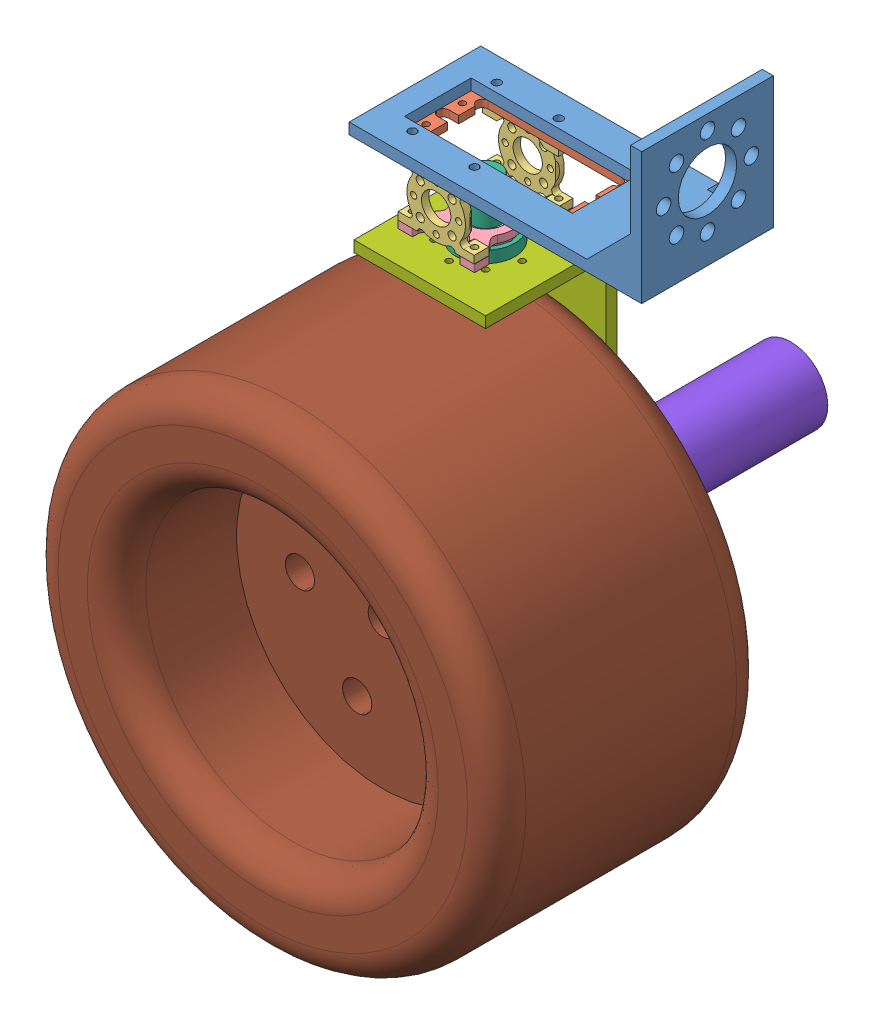
SolidWorks assembly Front_wheel_SUBASSEM, configuration Default. Lengths in mm.
Overall size (203.2 317.83 229.31).
18 component instances, 11 part files, 21 mates.
Components (placement in the parent):
- Servo_base_front-1: Servo_base_front [Default] at (66.9376 47.4067 44.7676) size (127 57.15 57.15)
- servo_mount-1: servo_mount [Default] at (63.4948 44.2317 73.3426) size (79.25 3.17 42.93)
- wheel_hold_left_right-1: wheel_hold_left_right [Default] at (47.8121 31.5317 51.8796) x (0 -1 0) z (-1 0 0) size (25.4 6.35 33.02)
- wheel_hold_left_right-2: wheel_hold_left_right [Default] at (47.8121 31.5317 94.8056) x (0 1 0) z (-1 0 0) size (25.4 6.35 33.02)
- Bearing_mount_subsubass-1: Bearing_mount_subsubass [Default] at (82.6306 37.2877 87.6325) x (0 0 -1) z (-1 0 0) size (42.93 5.08 33.27)
  - 535182-1: 535182 [Default] at (14.2899 18.456 34.8186) size (42.93 5.08 33.27)
  - .5 x .75 non flanged bearing-1: .5 x .75 non flanged bearing [Default] at (14.2899 19.5736 34.8186) x (0.770155 0 0.637857) z (-0.637857 0 0.770155) size (19.05 3.91 19.05)
- Mounting_hub_circular_servo-1: Mounting_hub_circular_servo [Default] at (47.8121 8.9765 73.3426) x (-0.707107 0 -0.707107) z (0.707107 0 -0.707107) size (25.39 25.4 25.39)
- Wheel_extension_sheet-2: Wheel_extension_sheet [Default] at (19.2371 8.9765 101.9176) size (57.15 139.7 57.15)
- Motor_and_mount_subass-1: Motor_and_mount_subass [Default] at (28.0226 -206.4882 -27.8911) x (0.696282 0.717769 0) z (0 0 1) size (46.7 46.7 115)
  - Motors-1: Motors [Default] at (81.834 51.8135 -31.3435) size (32 32 115)
  - Motor_mount-2: Motor_mount [Default] at (45.268 5.1287 35.3702) x (-0.707107 -0.707107 0) z (-0.707107 0.707107 0) size (33.02 8.74 33.02)
    - 555174-1: 555174 [Default] at (-58.8675 33.2863 7.1552) size (33.02 4.05 33.02)
    - 555174 screw_92005A116-1: 555174 screw_92005A116 [Default] at (-68.0596 28.5563 -2.0369) x (1 0 0) z (0 1 0) size (6 6 8.48)
    - 555174 screw_92005A116-2: 555174 screw_92005A116 [Default] at (-68.0596 28.5563 16.3474) x (0 0 -1) z (0 1 0) size (6 6 8.48)
    - 555174 screw_92005A116-3: 555174 screw_92005A116 [Default] at (-49.6753 28.5563 16.3474) x (-1 0 0) z (0 1 0) size (6 6 8.48)
    - 555174 screw_92005A116-4: 555174 screw_92005A116 [Default] at (-49.6753 28.5563 -2.0369) x (0 0 1) z (0 1 0) size (6 6 8.48)
- wheel_exa_1-1: wheel_exa_1 [Default] at (47.8121 -111.6735 55.7793) size (203.2 203.2 116.84)
Mates (geometry in assembly coordinates):
- Concentric1: concentric anti-aligned: cylinder of Servo_base_front-1 through (61.2824 47.4067 91.6306) axis (0 1 0) radius 1.778; cylinder of servo_mount-1 through (61.2824 47.4067 91.6306) axis (0 -1 0) radius 1.778
- Concentric2: concentric anti-aligned: cylinder of Servo_base_front-1 through (34.3417 47.4067 91.6306) axis (0 1 0) radius 1.778; cylinder of servo_mount-1 through (34.3417 47.4067 91.6306) axis (0 -1 0) radius 1.778
- Concentric3: concentric anti-aligned: cylinder of Servo_base_front-1 through (61.2824 47.4067 55.0546) axis (0 1 0) radius 1.778; cylinder of servo_mount-1 through (61.2824 47.4067 55.0546) axis (0 -1 0) radius 1.778
- Coincident1: coincident anti-aligned: plane of Servo_base_front-1 through (17.1576 47.4067 101.9176) normal (0 -1 0); plane of servo_mount-1 through (55.8849 47.4067 54.1021) normal (0 1 0)
- Concentric4: concentric aligned: cylinder of servo_mount-1 through (61.2824 47.4067 55.0546) axis (0 -1 0) radius 1.778; cylinder of wheel_hold_left_right-1 through (61.2824 40.938 55.0546) axis (0 -1 0) radius 1.3526
- Concentric5: concentric anti-aligned: cylinder of servo_mount-1 through (34.3417 47.4067 55.0546) axis (0 -1 0) radius 1.778; cylinder of wheel_hold_left_right-1 through (34.3417 44.2317 55.0546) axis (0 1 0) radius 1.3526
- Coincident2: coincident anti-aligned: plane of servo_mount-1 through (55.8849 44.2317 54.1021) normal (0 -1 0); plane of wheel_hold_left_right-1 through (47.8121 44.2317 39.7407) normal (0 1 0)
- Concentric6: concentric aligned: cylinder of servo_mount-1 through (34.3417 47.4067 91.6306) axis (0 -1 0) radius 1.778; cylinder of wheel_hold_left_right-2 through (34.3417 40.938 91.6306) axis (0 -1 0) radius 1.3526
- Concentric7: concentric anti-aligned: cylinder of servo_mount-1 through (61.2824 47.4067 91.6306) axis (0 -1 0) radius 1.778; cylinder of wheel_hold_left_right-2 through (61.2824 44.2317 91.6306) axis (0 1 0) radius 1.3526
- Coincident3: coincident anti-aligned: plane of servo_mount-1 through (55.8849 44.2317 54.1021) normal (0 -1 0); plane of wheel_hold_left_right-2 through (47.8121 44.2317 106.9446) normal (0 1 0)
- Concentric8: concentric anti-aligned: circle of wheel_hold_left_right-1; cylinder of Bearing_mount_subsubass-1/535182-1 through (34.3417 15.6567 55.0546) axis (0 -1 0) radius 1.778
- Concentric9: concentric aligned: cylinder of wheel_hold_left_right-2 through (34.3417 18.8317 91.6306) axis (0 -1 0) radius 1.3526; cylinder of Bearing_mount_subsubass-1/535182-1 through (34.3417 15.6567 91.6306) axis (0 -1 0) radius 1.778
- Coincident4: coincident anti-aligned: plane of wheel_hold_left_right-1 through (47.8121 18.8317 39.7407) normal (0 -1 0); plane of Bearing_mount_subsubass-1/535182-1 through (47.8121 18.8317 73.3426) normal (0 1 0)
- Concentric10: concentric anti-aligned: cylinder of Bearing_mount_subsubass-1/.5 x .75 non flanged bearing-1 through (47.8121 13.8025 73.3426) axis (0 1 0) radius 6.35; cylinder of Mounting_hub_circular_servo-1 through (47.8121 34.3765 73.3426) axis (0 -1 0) radius 6.3462
- Coincident5: coincident anti-aligned: plane of Bearing_mount_subsubass-1/.5 x .75 non flanged bearing-1 through (47.8121 14.0565 73.3426) normal (0 -1 0); plane of Mounting_hub_circular_servo-1 through (38.8345 14.0565 64.3651) normal (0 1 0)
- Parallel2: parallel aligned: line of Servo_base_front-1 through (120.3789 52.2327 44.7676) axis (-1 0 0); line of Wheel_extension_sheet-2 through (76.3871 8.9765 44.7676) axis (-1 0 0)
- Concentric27: concentric aligned: circle of Wheel_extension_sheet-2; cylinder of Motor_and_mount_subass-1/Motors-1 through (47.8121 -111.6735 55.7655) axis (0 0 -1) radius 3
- Concentric28: concentric aligned: cylinder of Mounting_hub_circular_servo-1 through (38.0331 14.0565 73.3426) axis (0 1 0) radius 1.3526; cylinder of Wheel_extension_sheet-2 through (38.0331 8.9765 73.3426) axis (0 1 0) radius 1.3526
- Concentric29: concentric aligned: cylinder of Mounting_hub_circular_servo-1 through (57.5911 14.0565 73.3426) axis (0 1 0) radius 1.3526; cylinder of Wheel_extension_sheet-2 through (57.5911 8.9765 73.3426) axis (0 1 0) radius 1.3526
- Coincident6: coincident anti-aligned: plane of Mounting_hub_circular_servo-1 through (47.8121 8.9765 73.3426) normal (0 -1 0); plane of Wheel_extension_sheet-2 through (76.3871 8.9765 101.9176) normal (0 1 0)
- Concentric30: concentric anti-aligned: cylinder of Motor_and_mount_subass-1/Motors-1 through (47.8121 -111.6735 55.7655) axis (0 0 -1) radius 3; cylinder of wheel_exa_1-1 through (47.8121 -111.6735 53.2393) axis (0 0 1) radius 6.35
